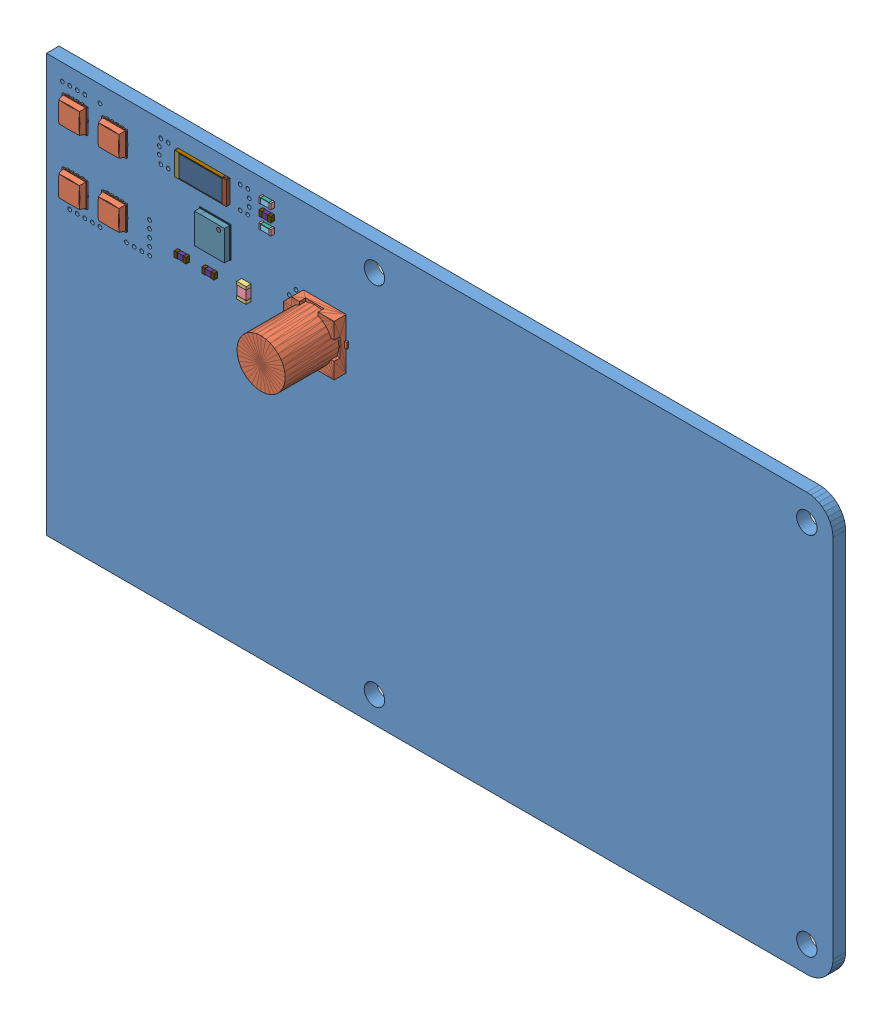
SolidWorks assembly Motor_Control_Board, configuration Default. Lengths in mm.
Overall size (105.51 56.01 9.74).
209 component instances, 51 part files, 0 mates.
Components (placement in the parent):
- Board-1: Board [Default] at (0 0 -1.6914) size (105.51 56.01 1.69)
- C1-1: C1 [Default] at origin size (7.39 6.81 8.05)
  - PCAP_6_3x7_7-ELECT-M-1: PCAP_6_3x7_7-ELECT-M [Default] at (123.8505 184.4041 0) x (1 0 0) z (0 0 1) size (7.39 6.81 8.05)
- C2-1: C2 [Default] at origin size (1.27 2.06 0.66)
  - 642826464-1: 642826464 [Default] at (113.8174 184.7342 0) size (1.27 0.41 0.66)
    - Extruded-1: Extruded [Default] at origin size (1.27 0.41 0.66)
  - 642826464-2: 642826464 [Default] at (113.8174 183.0832 0) size (1.27 0.41 0.66)
    - Extruded-1: Extruded [Default] at origin size (1.27 0.41 0.66)
  - 642826720-1: 642826720 [Default] at (113.8174 183.9087 0) size (1.22 2.01 0.64)
    - Extruded_2-1: Extruded_2 [Default] at origin size (1.22 2.01 0.64)
  - 642825824-1: 642825824 [Default] at (114.0079 184.2834 0.5588) size (0.38 0.19 0.03)
    - Extruded_3-1: Extruded_3 [Default] at origin size (0.38 0.19 0.03)
  - 642829792-1: 642829792 [Default] at (114.0079 184.0293 0.5588) size (0.38 0.19 0.13)
    - Extruded_4-1: Extruded_4 [Default] at origin size (0.38 0.19 0.13)
  - 642829664-1: 642829664 [Default] at (114.0079 183.2673 0.5588) size (0.38 0.25 0.13)
    - Extruded_5-1: Extruded_5 [Default] at origin size (0.38 0.25 0.13)
  - 642829536-1: 642829536 [Default] at (114.0079 183.7753 0.5588) size (0.38 0.25 0.13)
    - Extruded_6-1: Extruded_6 [Default] at origin size (0.38 0.25 0.13)
  - 642829408-1: 642829408 [Default] at (113.5634 183.8896 0.5588) size (0.38 0.19 0.03)
    - Extruded_7-1: Extruded_7 [Default] at origin size (0.38 0.19 0.03)
  - 642829280-1: 642829280 [Default] at (113.5634 183.6357 0.5588) size (0.38 0.19 0.03)
    - Extruded_8-1: Extruded_8 [Default] at origin size (0.38 0.19 0.03)
  - 642829152-1: 642829152 [Default] at (113.5634 183.3817 0.5588) size (0.38 0.19 0.03)
    - Extruded_9-1: Extruded_9 [Default] at origin size (0.38 0.19 0.03)
  - 642829024-1: 642829024 [Default] at (113.5634 183.1277 0.5588) size (0.38 0.25 0.13)
    - Extruded_10-1: Extruded_10 [Default] at origin size (0.38 0.25 0.13)
  - 642828896-1: 642828896 [Default] at (114.0079 183.5213 0.5588) size (0.38 0.19 0.03)
    - Extruded_11-1: Extruded_11 [Default] at origin size (0.38 0.19 0.03)
  - 642828768-1: 642828768 [Default] at (113.5634 184.1436 0.5588) size (0.38 0.19 0.03)
    - Extruded_12-1: Extruded_12 [Default] at origin size (0.38 0.19 0.03)
  - 642828512-1: 642828512 [Default] at (113.5634 184.3976 0.5588) size (0.38 0.19 0.03)
    - Extruded_13-1: Extruded_13 [Default] at origin size (0.38 0.19 0.03)
- C3-1: C3 [Default] at origin size (1.6 0.76 0.48)
  - 642828384-1: 642828384 [Default] at (109.6518 183.5634 0.254) size (0.13 0.25 0.03)
    - Extruded_14-1: Extruded_14 [Default] at origin size (0.13 0.25 0.03)
  - 642828128-1: 642828128 [Default] at (109.1565 183.7412 0) size (1.55 0.71 0.46)
    - Extruded_15-1: Extruded_15 [Default] at origin size (1.55 0.71 0.46)
  - 642828000-1: 642828000 [Default] at (109.7534 183.7412 0) size (0.41 0.76 0.48)
    - Extruded_16-1: Extruded_16 [Default] at origin size (0.41 0.76 0.48)
  - 642828000-2: 642828000 [Default] at (108.5596 183.7412 0) size (0.41 0.76 0.48)
    - Extruded_16-1: Extruded_16 [Default] at origin size (0.41 0.76 0.48)
  - 642827872-1: 642827872 [Default] at (109.2708 183.5634 0.254) size (0.13 0.25 0.03)
    - Extruded_17-1: Extruded_17 [Default] at origin size (0.13 0.25 0.03)
  - 642827616-1: 642827616 [Default] at (109.2708 183.9444 0.254) size (0.13 0.25 0.03)
    - Extruded_18-1: Extruded_18 [Default] at origin size (0.13 0.25 0.03)
  - 642827488-1: 642827488 [Default] at (109.0803 183.9444 0.254) size (0.13 0.25 0.03)
    - Extruded_19-1: Extruded_19 [Default] at origin size (0.13 0.25 0.03)
  - 642827360-1: 642827360 [Default] at (108.6993 183.9444 0.254) size (0.19 0.25 0.13)
    - Extruded_20-1: Extruded_20 [Default] at origin size (0.19 0.25 0.13)
  - 642827232-1: 642827232 [Default] at (108.8898 183.9444 0.254) size (0.13 0.25 0.03)
    - Extruded_21-1: Extruded_21 [Default] at origin size (0.13 0.25 0.03)
  - 642826976-1: 642826976 [Default] at (109.4613 183.9444 0.254) size (0.13 0.25 0.03)
    - Extruded_22-1: Extruded_22 [Default] at origin size (0.13 0.25 0.03)
  - 642827104-1: 642827104 [Default] at (109.6518 183.9444 0.254) size (0.13 0.25 0.03)
    - Extruded_23-1: Extruded_23 [Default] at origin size (0.13 0.25 0.03)
  - 642829920-1: 642829920 [Default] at (109.0803 183.5634 0.254) size (0.13 0.25 0.03)
    - Extruded_24-1: Extruded_24 [Default] at origin size (0.13 0.25 0.03)
  - 642830176-1: 642830176 [Default] at (108.8898 183.5634 0.254) size (0.13 0.25 0.03)
    - Extruded_25-1: Extruded_25 [Default] at origin size (0.13 0.25 0.03)
  - 642830304-1: 642830304 [Default] at (108.6993 183.5634 0.254) size (0.13 0.25 0.03)
    - Extruded_26-1: Extruded_26 [Default] at origin size (0.13 0.25 0.03)
- C4-1: C4 [Default] at origin size (1.6 0.76 0.48)
  - 642830432-1: 642830432 [Default] at (116.2812 194.3608 0.254) size (0.13 0.25 0.03)
    - Extruded_27-1: Extruded_27 [Default] at origin size (0.13 0.25 0.03)
  - 642828128-1: 642828128 [Default] at (116.7765 194.183 0) size (1.55 0.71 0.46)
    - Extruded_15-1: Extruded_15 [Default] at origin size (1.55 0.71 0.46)
  - 642828000-1: 642828000 [Default] at (116.1796 194.183 0) size (0.41 0.76 0.48)
    - Extruded_16-1: Extruded_16 [Default] at origin size (0.41 0.76 0.48)
  - 642828000-2: 642828000 [Default] at (117.3734 194.183 0) size (0.41 0.76 0.48)
    - Extruded_16-1: Extruded_16 [Default] at origin size (0.41 0.76 0.48)
  - 642830688-1: 642830688 [Default] at (116.6622 194.3608 0.254) size (0.13 0.25 0.03)
    - Extruded_28-1: Extruded_28 [Default] at origin size (0.13 0.25 0.03)
  - 642830816-1: 642830816 [Default] at (116.6622 193.9798 0.254) size (0.13 0.25 0.03)
    - Extruded_29-1: Extruded_29 [Default] at origin size (0.13 0.25 0.03)
  - 577140176-1: 577140176 [Default] at (116.8527 193.9798 0.254) size (0.13 0.25 0.03)
    - Extruded_30-1: Extruded_30 [Default] at origin size (0.13 0.25 0.03)
  - 642827360-1: 642827360 [Default] at (117.2337 193.9798 0.254) size (0.19 0.25 0.13)
    - Extruded_20-1: Extruded_20 [Default] at origin size (0.19 0.25 0.13)
  - 477870864-1: 477870864 [Default] at (117.0432 193.9798 0.254) size (0.13 0.25 0.03)
    - Extruded_31-1: Extruded_31 [Default] at origin size (0.13 0.25 0.03)
  - 642828640-1: 642828640 [Default] at (116.4717 193.9798 0.254) size (0.13 0.25 0.03)
    - Extruded_32-1: Extruded_32 [Default] at origin size (0.13 0.25 0.03)
  - 577140432-1: 577140432 [Default] at (116.2812 193.9798 0.254) size (0.13 0.25 0.03)
    - Extruded_33-1: Extruded_33 [Default] at origin size (0.13 0.25 0.03)
  - 642829920-1: 642829920 [Default] at (116.8527 194.3608 0.254) size (0.13 0.25 0.03)
    - Extruded_24-1: Extruded_24 [Default] at origin size (0.13 0.25 0.03)
  - 577140560-1: 577140560 [Default] at (117.0432 194.3608 0.254) size (0.13 0.25 0.03)
    - Extruded_34-1: Extruded_34 [Default] at origin size (0.13 0.25 0.03)
  - 577140688-1: 577140688 [Default] at (117.2337 194.3608 0.254) size (0.13 0.25 0.03)
    - Extruded_35-1: Extruded_35 [Default] at origin size (0.13 0.25 0.03)
- C5-1: C5 [Default] at origin size (1.6 0.76 0.48)
  - 642828384-1: 642828384 [Default] at (105.9166 183.5634 0.254) size (0.13 0.25 0.03)
    - Extruded_14-1: Extruded_14 [Default] at origin size (0.13 0.25 0.03)
  - 642828128-1: 642828128 [Default] at (105.4213 183.7412 0) size (1.55 0.71 0.46)
    - Extruded_15-1: Extruded_15 [Default] at origin size (1.55 0.71 0.46)
  - 642828000-1: 642828000 [Default] at (106.0182 183.7412 0) size (0.41 0.76 0.48)
    - Extruded_16-1: Extruded_16 [Default] at origin size (0.41 0.76 0.48)
  - 642828000-2: 642828000 [Default] at (104.8244 183.7412 0) size (0.41 0.76 0.48)
    - Extruded_16-1: Extruded_16 [Default] at origin size (0.41 0.76 0.48)
  - 642827872-1: 642827872 [Default] at (105.5356 183.5634 0.254) size (0.13 0.25 0.03)
    - Extruded_17-1: Extruded_17 [Default] at origin size (0.13 0.25 0.03)
  - 642827616-1: 642827616 [Default] at (105.5356 183.9444 0.254) size (0.13 0.25 0.03)
    - Extruded_18-1: Extruded_18 [Default] at origin size (0.13 0.25 0.03)
  - 642827488-1: 642827488 [Default] at (105.3451 183.9444 0.254) size (0.13 0.25 0.03)
    - Extruded_19-1: Extruded_19 [Default] at origin size (0.13 0.25 0.03)
  - 642827360-1: 642827360 [Default] at (104.9641 183.9444 0.254) size (0.19 0.25 0.13)
    - Extruded_20-1: Extruded_20 [Default] at origin size (0.19 0.25 0.13)
  - 642827232-1: 642827232 [Default] at (105.1546 183.9444 0.254) size (0.13 0.25 0.03)
    - Extruded_21-1: Extruded_21 [Default] at origin size (0.13 0.25 0.03)
  - 642826976-1: 642826976 [Default] at (105.7261 183.9444 0.254) size (0.13 0.25 0.03)
    - Extruded_22-1: Extruded_22 [Default] at origin size (0.13 0.25 0.03)
  - 642827104-1: 642827104 [Default] at (105.9166 183.9444 0.254) size (0.13 0.25 0.03)
    - Extruded_23-1: Extruded_23 [Default] at origin size (0.13 0.25 0.03)
  - 642829920-1: 642829920 [Default] at (105.3451 183.5634 0.254) size (0.13 0.25 0.03)
    - Extruded_24-1: Extruded_24 [Default] at origin size (0.13 0.25 0.03)
  - 642830176-1: 642830176 [Default] at (105.1546 183.5634 0.254) size (0.13 0.25 0.03)
    - Extruded_25-1: Extruded_25 [Default] at origin size (0.13 0.25 0.03)
  - 642830304-1: 642830304 [Default] at (104.9641 183.5634 0.254) size (0.13 0.25 0.03)
    - Extruded_26-1: Extruded_26 [Default] at origin size (0.13 0.25 0.03)
- Q1-1: Q1 [Default] at origin size (3.99 3.99 1.61)
  - PowerPAK_1212-8_Single_Pad-1: PowerPAK_1212-8_Single_Pad [Default] at (96.1999 192.9 0) x (1 0 0) z (0 -1 0) size (3.99 1.6 3.99)
  - PowerPAK_1212-8_Single_Pad_2-1: PowerPAK_1212-8_Single_Pad_2 [Default] at (96.1999 192.9 0) x (1 0 0) z (0 -1 0) size (3.55 0.28 3.55)
- Q2-1: Q2 [Default] at origin size (3.99 3.99 1.61)
  - PowerPAK_1212-8_Single_Pad-1: PowerPAK_1212-8_Single_Pad [Default] at (96.2001 184.3 0) x (-1 0 0) z (0 1 0) size (3.99 1.6 3.99)
  - PowerPAK_1212-8_Single_Pad_2-1: PowerPAK_1212-8_Single_Pad_2 [Default] at (96.2001 184.3 0) x (-1 0 0) z (0 1 0) size (3.55 0.28 3.55)
- Q3-1: Q3 [Default] at origin size (3.99 3.99 1.61)
  - PowerPAK_1212-8_Single_Pad-1: PowerPAK_1212-8_Single_Pad [Default] at (90.9001 192.8999 0) x (-1 0 0) z (0 1 0) size (3.99 1.6 3.99)
  - PowerPAK_1212-8_Single_Pad_2-1: PowerPAK_1212-8_Single_Pad_2 [Default] at (90.9001 192.8999 0) x (-1 0 0) z (0 1 0) size (3.55 0.28 3.55)
- Q4-1: Q4 [Default] at origin size (3.99 3.99 1.61)
  - PowerPAK_1212-8_Single_Pad-1: PowerPAK_1212-8_Single_Pad [Default] at (90.8999 184.3 0) x (1 0 0) z (0 -1 0) size (3.99 1.6 3.99)
  - PowerPAK_1212-8_Single_Pad_2-1: PowerPAK_1212-8_Single_Pad_2 [Default] at (90.8999 184.3 0) x (1 0 0) z (0 -1 0) size (3.55 0.28 3.55)
- R1-1: R1 [Default] at origin size (1.6 0.76 0.48)
  - 642830304-1: 642830304 [Default] at (116.3828 192.5193 0.381) size (0.13 0.25 0.03)
    - Extruded_26-1: Extruded_26 [Default] at origin size (0.13 0.25 0.03)
  - 642830176-1: 642830176 [Default] at (116.5733 192.5193 0.381) size (0.13 0.25 0.03)
    - Extruded_25-1: Extruded_25 [Default] at origin size (0.13 0.25 0.03)
  - 642829920-1: 642829920 [Default] at (116.7638 192.5193 0.381) size (0.13 0.25 0.03)
    - Extruded_24-1: Extruded_24 [Default] at origin size (0.13 0.25 0.03)
  - 642827104-1: 642827104 [Default] at (117.2464 192.7987 0.381) size (0.13 0.25 0.03)
    - Extruded_23-1: Extruded_23 [Default] at origin size (0.13 0.25 0.03)
  - 642826976-1: 642826976 [Default] at (117.0559 192.7987 0.381) size (0.13 0.25 0.03)
    - Extruded_22-1: Extruded_22 [Default] at origin size (0.13 0.25 0.03)
  - 642827232-1: 642827232 [Default] at (116.4844 192.7987 0.381) size (0.13 0.25 0.03)
    - Extruded_21-1: Extruded_21 [Default] at origin size (0.13 0.25 0.03)
  - 577140816-1: 577140816 [Default] at (116.0907 192.659 0) size (0.23 0.76 0.48)
    - Extruded_36-1: Extruded_36 [Default] at origin size (0.23 0.76 0.48)
  - 577140816-2: 577140816 [Default] at (117.4623 192.659 0) size (0.23 0.76 0.48)
    - Extruded_36-1: Extruded_36 [Default] at origin size (0.23 0.76 0.48)
  - 577140944-1: 577140944 [Default] at (116.7765 192.659 0.4572) size (1.14 0.66 0.03)
    - Extruded_37-1: Extruded_37 [Default] at origin size (1.14 0.66 0.03)
  - 577141072-1: 577141072 [Default] at (116.7765 192.659 0) size (1.55 0.71 0.46)
    - Extruded_38-1: Extruded_38 [Default] at origin size (1.55 0.71 0.46)
  - 642827360-1: 642827360 [Default] at (116.2939 192.7987 0.381) size (0.19 0.25 0.13)
    - Extruded_20-1: Extruded_20 [Default] at origin size (0.19 0.25 0.13)
  - 642827488-1: 642827488 [Default] at (116.6749 192.7987 0.381) size (0.13 0.25 0.03)
    - Extruded_19-1: Extruded_19 [Default] at origin size (0.13 0.25 0.03)
  - 642827616-1: 642827616 [Default] at (116.8654 192.7987 0.381) size (0.13 0.25 0.03)
    - Extruded_18-1: Extruded_18 [Default] at origin size (0.13 0.25 0.03)
  - 642827872-1: 642827872 [Default] at (116.9543 192.5193 0.381) size (0.13 0.25 0.03)
    - Extruded_17-1: Extruded_17 [Default] at origin size (0.13 0.25 0.03)
  - 577141456-1: 577141456 [Default] at (117.1448 192.5193 0.381) size (0.14 0.25 0.13)
    - Extruded_39-1: Extruded_39 [Default] at origin size (0.14 0.25 0.13)
- R2-1: R2 [Default] at origin size (1.6 0.76 0.48)
  - 577140688-1: 577140688 [Default] at (117.1702 195.8467 0.381) size (0.13 0.25 0.03)
    - Extruded_35-1: Extruded_35 [Default] at origin size (0.13 0.25 0.03)
  - 577140560-1: 577140560 [Default] at (116.9797 195.8467 0.381) size (0.13 0.25 0.03)
    - Extruded_34-1: Extruded_34 [Default] at origin size (0.13 0.25 0.03)
  - 642829920-1: 642829920 [Default] at (116.7892 195.8467 0.381) size (0.13 0.25 0.03)
    - Extruded_24-1: Extruded_24 [Default] at origin size (0.13 0.25 0.03)
  - 577140432-1: 577140432 [Default] at (116.3066 195.5673 0.381) size (0.13 0.25 0.03)
    - Extruded_33-1: Extruded_33 [Default] at origin size (0.13 0.25 0.03)
  - 642828640-1: 642828640 [Default] at (116.4971 195.5673 0.381) size (0.13 0.25 0.03)
    - Extruded_32-1: Extruded_32 [Default] at origin size (0.13 0.25 0.03)
  - 477870864-1: 477870864 [Default] at (117.0686 195.5673 0.381) size (0.13 0.25 0.03)
    - Extruded_31-1: Extruded_31 [Default] at origin size (0.13 0.25 0.03)
  - 577140816-1: 577140816 [Default] at (117.4623 195.707 0) size (0.23 0.76 0.48)
    - Extruded_36-1: Extruded_36 [Default] at origin size (0.23 0.76 0.48)
  - 577140816-2: 577140816 [Default] at (116.0907 195.707 0) size (0.23 0.76 0.48)
    - Extruded_36-1: Extruded_36 [Default] at origin size (0.23 0.76 0.48)
  - 577140944-1: 577140944 [Default] at (116.7765 195.707 0.4572) size (1.14 0.66 0.03)
    - Extruded_37-1: Extruded_37 [Default] at origin size (1.14 0.66 0.03)
  - 577141072-1: 577141072 [Default] at (116.7765 195.707 0) size (1.55 0.71 0.46)
    - Extruded_38-1: Extruded_38 [Default] at origin size (1.55 0.71 0.46)
  - 642827360-1: 642827360 [Default] at (117.2591 195.5673 0.381) size (0.19 0.25 0.13)
    - Extruded_20-1: Extruded_20 [Default] at origin size (0.19 0.25 0.13)
  - 577140176-1: 577140176 [Default] at (116.8781 195.5673 0.381) size (0.13 0.25 0.03)
    - Extruded_30-1: Extruded_30 [Default] at origin size (0.13 0.25 0.03)
  - 642830816-1: 642830816 [Default] at (116.6876 195.5673 0.381) size (0.13 0.25 0.03)
    - Extruded_29-1: Extruded_29 [Default] at origin size (0.13 0.25 0.03)
  - 642830688-1: 642830688 [Default] at (116.5987 195.8467 0.381) size (0.13 0.25 0.03)
    - Extruded_28-1: Extruded_28 [Default] at origin size (0.13 0.25 0.03)
  - 577141200-1: 577141200 [Default] at (116.4082 195.8467 0.381) size (0.14 0.25 0.13)
    - Extruded_40-1: Extruded_40 [Default] at origin size (0.14 0.25 0.13)
- R3-1: R3 [Default] at origin size (6.99 3.09 0.48)
  - 577141712-1: 577141712 [Default] at (108.135 194.2764 0) size (6.9 3.09 0.46)
    - Extruded_41-1: Extruded_41 [Default] at origin size (6.9 3.09 0.46)
  - 577141840-1: 577141840 [Default] at (108.135 194.2827 0.4572) size (5.78 2.84 0.03)
    - Extruded_42-1: Extruded_42 [Default] at origin size (5.78 2.84 0.03)
  - 577141968-1: 577141968 [Default] at (111.3228 194.2764 0) size (0.6 3.09 0.48)
    - Extruded_43-1: Extruded_43 [Default] at origin size (0.6 3.09 0.48)
  - 477873424-1: 477873424 [Default] at (104.941 194.2764 0) size (0.61 3.09 0.48)
    - Extruded_44-1: Extruded_44 [Default] at origin size (0.61 3.09 0.48)
- U1-1: U1 [Default] at origin size (4.15 4.15 0.8)
  - 577142096-1: 577142096 [Default] at (110.9011 189.8396 0.8) size (0.52 0.52 0.01)
    - Extruded_45-1: Extruded_45 [Default] at origin size (0.52 0.52 0.01)
  - 577141584-1: 577141584 [Default] at (109.6772 188.3918 0.1) size (4.01 4.01 0.7)
    - Extruded_46-1: Extruded_46 [Default] at origin size (4.01 4.01 0.7)
  - 577142224-1: 577142224 [Default] at (109.685 188.425 0.01) size (4.15 4.15 0.09)
    - Extruded_47-1: Extruded_47 [Default] at origin size (4.15 4.15 0.09)
